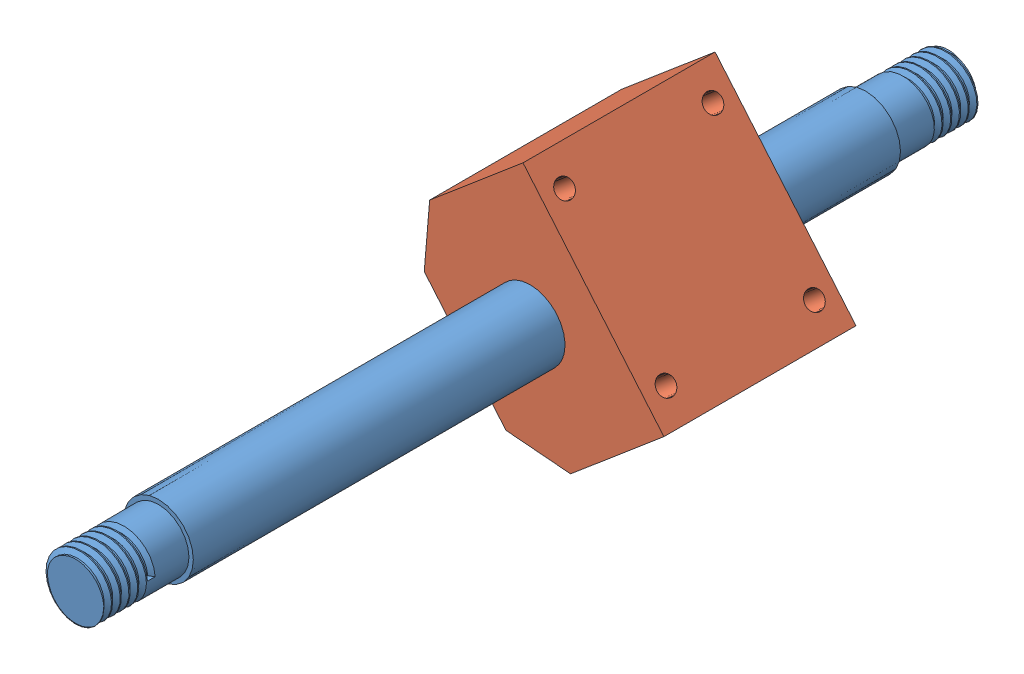
SolidWorks assembly Z slide, configuration Default. Lengths in mm.
Overall size (61.68 63.04 202.39).
2 component instances, 2 part files, 1 mates.
Components (placement in the parent):
- Z rod-1: Z rod [Default] at (118.7688 177.4566 348.0591) size (16 16 202.39)
- sliding block-1: sliding block [Default] at (103.8764 164.8683 290.4329) x (-0.645556 0.763713 0) z (0.763713 0.645556 0) size (50 44 38.5)
Mates (geometry in assembly coordinates):
- Concentric1: concentric aligned: cylinder of Z rod-1 through (118.7688 177.4566 417.0821) axis (0 0 1) radius 8; cylinder of sliding block-1 through (118.7688 177.4566 268.4329) axis (0 0 1) radius 8
